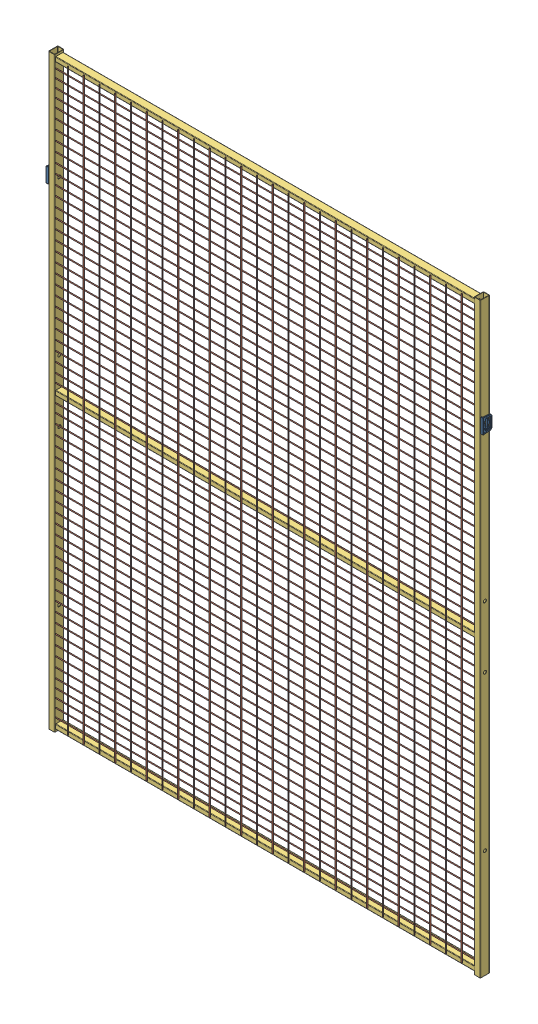
SolidWorks assembly W322-190140-Axelent, configuration Default. Lengths in mm.
Overall size (1415.63 1900 30).
4 component instances, 3 part files, 0 mates.
Components (placement in the parent):
- G2032-1: G2032 [Default] at (699 600 0) x (-1 0 0) z (0 0 1) size (9.31 48.01 29.42)
- G2032-2: G2032 [Default] at (-699 600 0) size (9.31 48.01 29.42)
- NÄT-50x30_II_N-05030-190-140-1: NÄT-50x30_II_N-05030-190-140 [Default] at (0 0 13.5) x (-1 0 0) z (0 0 -1) size (1380 1876 4.75)
- RAM-30_RAM-190-140-1: RAM-30_RAM-190-140 [Default] at origin size (1398 1900 30)
